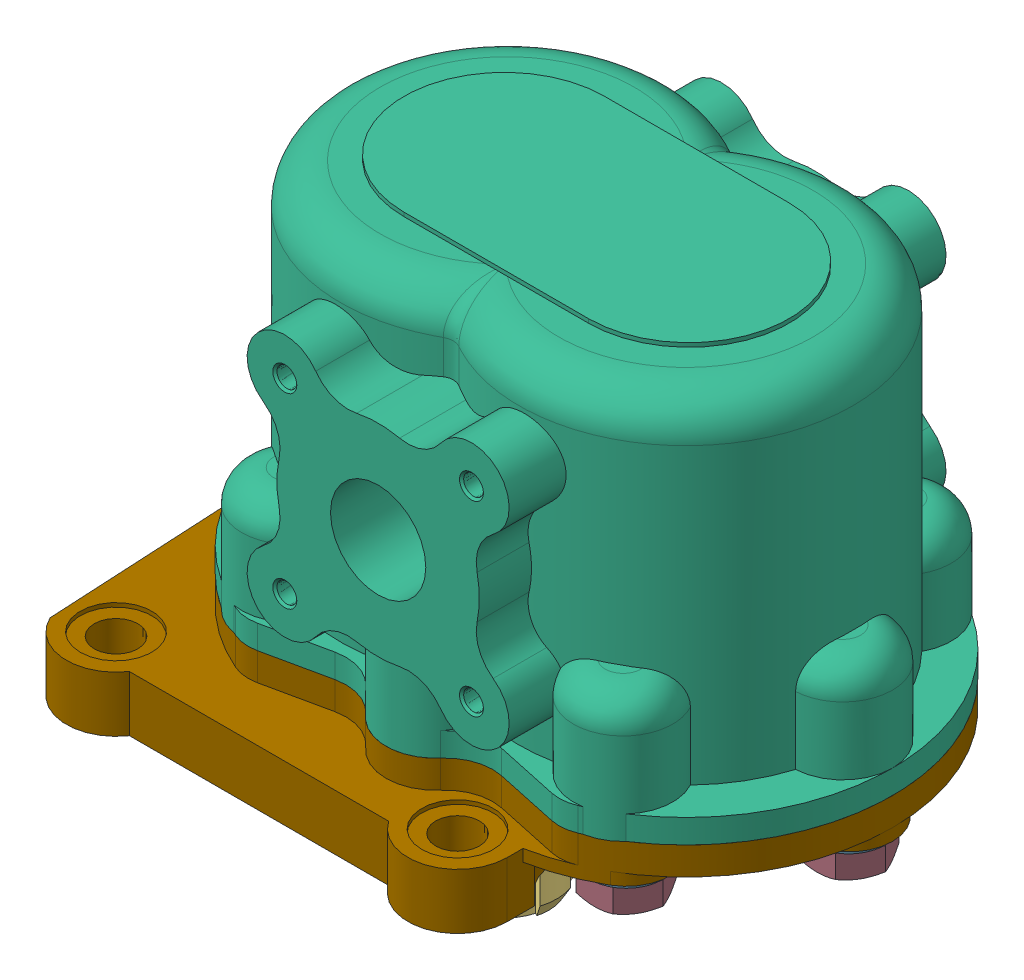
SolidWorks assembly НШ 32, configuration По умолчанию. Lengths in mm.
Overall size (155 159.25 135).
32 component instances, 14 part files, 43 mates.
Components (placement in the parent):
- Проставка 1-1: Проставка 1 [По умолчанию] at (0 53.25 0) size (100 12 55)
- Вал-шестерня ведомый-1: Вал-шестерня ведомый [По умолчанию] at (22.5 84.25 0) x (0 -1 0) z (0.682448 0 -0.730934) size (83.5 55 55)
- Вал-шестерня ведущий-1: Вал-шестерня ведущий [По умолчанию] at (-22.5 -68.25 0) x (0 1 0) z (-0.999747 0 0.022504) size (152 55 55)
- Втулка опорная 1-1: Втулка опорная 1 [По умолчанию] at (22.5 85 0) x (1 0 0) z (0 0 -1) size (50 19.75 55)
- Втулка опорная 2-1: Втулка опорная 2 [По умолчанию] at (-22.5 85 0) x (-1 0 0) z (0 0 1) size (50 19.75 55)
- Проставка 1-2: Проставка 1 [По умолчанию] at (0 31.75 0) x (-1 0 0) z (0 0 1) size (100 12 55)
- Втулка опорная 1-2: Втулка опорная 1 [По умолчанию] at (-22.5 19.75 0) x (-1 0 0) z (0 0 1) size (50 19.75 55)
- Втулка опорная 2-2: Втулка опорная 2 [По умолчанию] at (22.5 19.75 0) x (1 0 0) z (0 0 -1) size (50 19.75 55)
- Корпус-1: Корпус [По умолчанию] at origin size (149 91 110)
- Прокладка-1: Прокладка [По умолчанию] at origin size (111 2 66)
- Манжета-1: Манжета [По умолчанию] at (-0.1256 19.75 -2.8972) x (0.999286 0 -0.037784) z (0.037784 0 0.999286) size (100 6 53.49)
- Манжета-2: Манжета [По умолчанию] at (0 65.25 -3.75) x (-1 0 0) z (0 0 1) size (100 6 53.49)
- Крышка-1: Крышка [По умолчанию] x (1 0 0) z (0 0 -1) size (155 27 135)
- circlip for bores normal_din-3: circlip for bores normal_din [Circlip DIN 472 - 42 x 1.75] at (-22.5 -24.75 0) x (1 0 0) z (0 -1 0) size (44.5 43.63 1.75)
- Шайба-1: Шайба [По умолчанию] at (-22.5 -23 0) x (0 1 0) z (0.059955 0 0.998201) size (5 42 42)
- CR_25X42X10_HMS5_V_PART1-1: CR_25X42X10_HMS5_V_PART1 [По умолчанию] at (-22.5 -22 0) x (0 1 0) z (0 0 1) size (10 42 42)
- hex bolt gradeb_din-4: hex bolt gradeb_din [ISO 4015 - M10 x 40 x 40-N] at (-43 -18.2 -35.507) x (0 1 0) z (0 0 1) size (46.4 18.48 16)
- curved spring lock washer_din-73: curved spring lock washer_din [Spring washer DIN 128 - A10] at (-43 -11.8 -35.507) x (0 -1 0) z (0 0 1) size (1.86 18.1 18.09)
- curved spring lock washer_din-75: curved spring lock washer_din [Spring washer DIN 128 - A10] at (43 -11.8 35.507) x (0 -1 0) z (0 0 1) size (1.86 18.1 18.09)
- curved spring lock washer_din-76: curved spring lock washer_din [Spring washer DIN 128 - A10] at (43 -11.8 -35.507) x (0 -1 0) z (0 0 1) size (1.86 18.1 18.09)
- curved spring lock washer_din-78: curved spring lock washer_din [Spring washer DIN 128 - A10] at (0 -11.8 -40.5) x (0 -1 0) z (0 0 1) size (1.86 18.1 18.09)
- curved spring lock washer_din-79: curved spring lock washer_din [Spring washer DIN 128 - A10] at (-43 -11.8 35.507) x (0 -1 0) z (0 0 1) size (1.86 18.1 18.09)
- curved spring lock washer_din-80: curved spring lock washer_din [Spring washer DIN 128 - A10] at (-63.5 -11.8 0) x (0 -1 0) z (0 0 1) size (1.86 18.1 18.09)
- curved spring lock washer_din-81: curved spring lock washer_din [Spring washer DIN 128 - A10] at (63.5 -11.8 0) x (0 -1 0) z (0 0 1) size (1.86 18.1 18.09)
- curved spring lock washer_din-82: curved spring lock washer_din [Spring washer DIN 128 - A10] at (0 -11.8 40.5) x (0 -1 0) z (0 0 1) size (1.86 18.1 18.09)
- hex bolt gradeb_din-6: hex bolt gradeb_din [ISO 4015 - M10 x 40 x 40-N] at (43 -18.2 35.507) x (0 1 0) z (0 0 1) size (46.4 18.48 16)
- hex bolt gradeb_din-7: hex bolt gradeb_din [ISO 4015 - M10 x 40 x 40-N] at (43 -18.2 -35.507) x (0 1 0) z (0 0 1) size (46.4 18.48 16)
- hex bolt gradeb_din-9: hex bolt gradeb_din [ISO 4015 - M10 x 40 x 40-N] at (0 -18.2 -40.5) x (0 1 0) z (0 0 1) size (46.4 18.48 16)
- hex bolt gradeb_din-10: hex bolt gradeb_din [ISO 4015 - M10 x 40 x 40-N] at (-43 -18.2 35.507) x (0 1 0) z (0 0 1) size (46.4 18.48 16)
- hex bolt gradeb_din-11: hex bolt gradeb_din [ISO 4015 - M10 x 40 x 40-N] at (-63.5 -18.2 0) x (0 1 0) z (0 0 1) size (46.4 18.48 16)
- hex bolt gradeb_din-12: hex bolt gradeb_din [ISO 4015 - M10 x 40 x 40-N] at (63.5 -18.2 0) x (0 1 0) z (0 0 1) size (46.4 18.48 16)
- hex bolt gradeb_din-13: hex bolt gradeb_din [ISO 4015 - M10 x 40 x 40-N] at (0 -18.2 40.5) x (0 1 0) z (0 0 1) size (46.4 18.48 16)
Mates (geometry in assembly coordinates):
- Концентричный1: concentric anti-aligned: cylinder of Проставка 1-1 through (22.5 65.25 0) axis (0 -1 0) radius 13; cylinder of Вал-шестерня ведомый-1 through (22.5 53.25 0) axis (0 1 0) radius 13
- Совпадение1: coincident anti-aligned: plane of Проставка 1-1 through (0 53.25 0) normal (0 -1 0); plane of Вал-шестерня ведомый-1 through (22.5 53.25 0) normal (0 1 0)
- Концентричный2: concentric aligned: cylinder of Проставка 1-1 through (-22.5 65.25 0) axis (0 -1 0) radius 13; cylinder of Вал-шестерня ведущий-1 through (-22.5 83.75 0) axis (0 -1 0) radius 13
- Совпадение2: coincident anti-aligned: plane of Проставка 1-1 through (0 53.25 0) normal (0 -1 0); plane of Вал-шестерня ведущий-1 through (-22.5 53.25 0) normal (0 1 0)
- Сопряжения редуктора1: gear = 55 : 55 mm: cylinder of Вал-шестерня ведущий-1 through (-22.5 70.1804 0) axis (0 -1 0) radius 27.5; cylinder of Вал-шестерня ведомый-1 through (22.5 16.6154 0) axis (0 1 0) radius 27.5
- Концентричный3: concentric aligned: cylinder of Вал-шестерня ведомый-1 through (22.5 53.25 0) axis (0 1 0) radius 13; cylinder of Втулка опорная 1-1 through (22.5 65.25 0) axis (0 1 0) radius 13
- Концентричный4: concentric anti-aligned: cylinder of Вал-шестерня ведущий-1 through (-22.5 83.75 0) axis (0 -1 0) radius 13; cylinder of Втулка опорная 2-1 through (-22.5 65.25 0) axis (0 1 0) radius 13
- Совпадение3: coincident anti-aligned: plane of Втулка опорная 1-1 through (0 65.25 15.8114) normal (-1 0 0); plane of Втулка опорная 2-1 through (0 65.25 -15.8114) normal (1 0 0)
- Совпадение4: coincident aligned: plane of Втулка опорная 1-1 through (22.5 85 0) normal (0 1 0); plane of Втулка опорная 2-1 through (-22.5 85 0) normal (0 1 0)
- Совпадение5: coincident anti-aligned: plane of Проставка 1-1 through (0 65.25 0) normal (0 1 0); plane of Втулка опорная 2-1 through (-22.5 65.25 0) normal (0 -1 0)
- Концентричный5: concentric aligned: cylinder of Вал-шестерня ведомый-1 through (22.5 0.75 0) axis (0 1 0) radius 13; cylinder of Проставка 1-2 through (22.5 19.75 0) axis (0 1 0) radius 13
- Концентричный6: concentric anti-aligned: cylinder of Вал-шестерня ведущий-1 through (-22.5 31.75 0) axis (0 -1 0) radius 13; cylinder of Проставка 1-2 through (-22.5 19.75 0) axis (0 1 0) radius 13
- Совпадение6: coincident anti-aligned: plane of Вал-шестерня ведомый-1 through (22.5 31.75 0) normal (0 -1 0); plane of Проставка 1-2 through (0 31.75 0) normal (0 1 0)
- Совпадение7: coincident aligned: plane of Корпус-1 through (0 0 0) normal (0 0 1); plane of assembly through (0 0 0) normal (0 0 1)
- Совпадение8: coincident aligned: plane of Корпус-1 through (0 0 0) normal (0 1 0); plane of assembly through (0 0 0) normal (0 1 0)
- Совпадение9: coincident aligned: plane of Корпус-1 through (0 0 0) normal (1 0 0); plane of assembly through (0 0 0) normal (1 0 0)
- Совпадение10: coincident anti-aligned: plane of Втулка опорная 2-1 through (-22.5 85 0) normal (0 1 0); plane of Корпус-1 through (0 85 0) normal (0 -1 0)
- Концентричный7: concentric anti-aligned: cylinder of Втулка опорная 2-1 through (-22.5 65.25 0) axis (0 1 0) radius 27.5; cylinder of Корпус-1 through (-22.5 85 0) axis (0 -1 0) radius 27.25
- Совпадение11: coincident anti-aligned: plane of Проставка 1-2 through (0 19.75 0) normal (0 -1 0); plane of Втулка опорная 2-2 through (22.5 19.75 0) normal (0 1 0)
- Концентричный8: concentric anti-aligned: cylinder of Втулка опорная 2-2 through (22.5 0 0) axis (0 1 0) radius 27.5; cylinder of Корпус-1 through (22.5 85 0) axis (0 -1 0) radius 27.25
- Концентричный9: concentric anti-aligned: cylinder of Втулка опорная 1-2 through (-22.5 0 0) axis (0 1 0) radius 27.5; cylinder of Корпус-1 through (-22.5 85 0) axis (0 -1 0) radius 27.25
- Совпадение12: coincident anti-aligned: plane of Втулка опорная 1-2 through (0 0 -15.8114) normal (1 0 0); plane of Втулка опорная 2-2 through (0 0 15.8114) normal (-1 0 0)
- Совпадение14: coincident anti-aligned: plane of Проставка 1-2 through (0 19.75 0) normal (0 -1 0); plane of Втулка опорная 1-2 through (-22.5 19.75 0) normal (0 1 0)
- Концентричный10: concentric aligned: cylinder of Корпус-1 through (-22.5 2 0) axis (0 -1 0) radius 33; cylinder of Прокладка-1 through (-22.5 2 0) axis (0 -1 0) radius 33
- Совпадение15: coincident anti-aligned: plane of Корпус-1 through (-22.5 2 0) normal (0 -1 0); plane of Прокладка-1 through (22.5 2 0) normal (0 1 0)
- Концентричный11: concentric aligned: cylinder of Проставка 1-2 through (22.5 25.75 0) axis (0 -1 0) radius 16.5; cylinder of Манжета-1 through (22.5 25.75 0) axis (0 -1 0) radius 16.5
- Совпадение16: coincident anti-aligned: plane of Втулка опорная 2-2 through (22.5 19.75 0) normal (0 1 0); plane of Манжета-1 through (-22.4679 19.75 1.7003) normal (0 -1 0)
- Концентричный12: concentric aligned: cylinder of Проставка 1-1 through (22.5 59.25 0) axis (0 1 0) radius 16.5; cylinder of Манжета-2 through (22.5 59.25 0) axis (0 1 0) radius 16.5
- Концентричный13: concentric aligned: cylinder of Проставка 1-1 through (-22.5 59.25 0) axis (0 1 0) radius 16.5; cylinder of Манжета-2 through (-22.5 59.25 0) axis (0 1 0) radius 16.5
- Совпадение19: coincident anti-aligned: plane of Втулка опорная 2-1 through (-22.5 65.25 0) normal (0 -1 0); plane of Манжета-2 through (22.5 65.25 0) normal (0 1 0)
- Совпадение20: coincident anti-aligned: plane of Корпус-1 through (0 0 -40.5) normal (0 -1 0); plane of Крышка-1 through (0 0 40.5) normal (0 1 0)
- Концентричный14: concentric aligned: cylinder of Вал-шестерня ведущий-1 through (-22.5 -18.25 0) axis (0 -1 0) radius 12.5; cylinder of Крышка-1 through (-22.5 0 0) axis (0 -1 0) radius 13.5
- Концентричный18: concentric anti-aligned: cylinder of Корпус-1 through (22.5 6 0) axis (0 -1 0) radius 52; cylinder of Крышка-1 through (22.5 -7 0) axis (0 1 0) radius 52
- Концентричный19: concentric aligned: cylinder of Крышка-1 through (-22.5 -74.6161 0) axis (0 -1 0) radius 22.5; cylinder of circlip for bores normal_din-3 through (-22.5 -23 0) axis (0 -1 0) radius 22.25
- Совпадение21: coincident anti-aligned: plane of Крышка-1 through (-45 -23 0) normal (0 -1 0); plane of circlip for bores normal_din-3 through (-22.5 -23 0) normal (0 1 0)
- Концентричный21: concentric aligned: cylinder of Крышка-1 through (-22.5 -12 0) axis (0 -1 0) radius 21; cylinder of Шайба-1 through (-22.5 -23 0) axis (0 -1 0) radius 21
- Совпадение24: coincident anti-aligned: plane of Крышка-1 through (-22.5 -12 0) normal (0 -1 0); plane of CR_25X42X10_HMS5_V_PART1-1 through (-40.6667 -12 0) normal (0 1 0)
- Концентричный22: concentric aligned: cylinder of Крышка-1 through (-22.5 -12 0) axis (0 -1 0) radius 21; cylinder of CR_25X42X10_HMS5_V_PART1-1 through (-22.5 -12.4722 0) axis (0 -1 0) radius 13.9167
- Совпадение25: coincident anti-aligned: plane of Шайба-1 through (-38.4712 -22 0.9593) normal (0 1 0); plane of CR_25X42X10_HMS5_V_PART1-1 through (-42.5556 -22 0) normal (0 -1 0)
- Концентричный24: concentric aligned: cylinder of Крышка-1 through (-43 -11 -35.507) axis (0 -1 0) radius 5.5; cylinder of hex bolt gradeb_din-4 through (-43 -18.2 -35.507) axis (0 -1 0) radius 5
- Концентричный25: concentric anti-aligned: cylinder of Крышка-1 through (-43 -11 -35.507) axis (0 -1 0) radius 5.5; cylinder of curved spring lock washer_din-73 through (-43 23.125 -35.507) axis (0 1 0) radius 9.05
- Совпадение27: coincident anti-aligned: plane of hex bolt gradeb_din-4 through (-51.0829 -11.8 -35.507) normal (0 1 0); plane of curved spring lock washer_din-73 through (-37.4 -11.8 -35.507) normal (0 -1 0)
- Совпадение28: coincident anti-aligned: plane of Крышка-1 through (-37.5 -10 -35.507) normal (0 -1 0); plane of curved spring lock washer_din-73 through (-33.95 -10 -35.507) normal (0 1 0)
